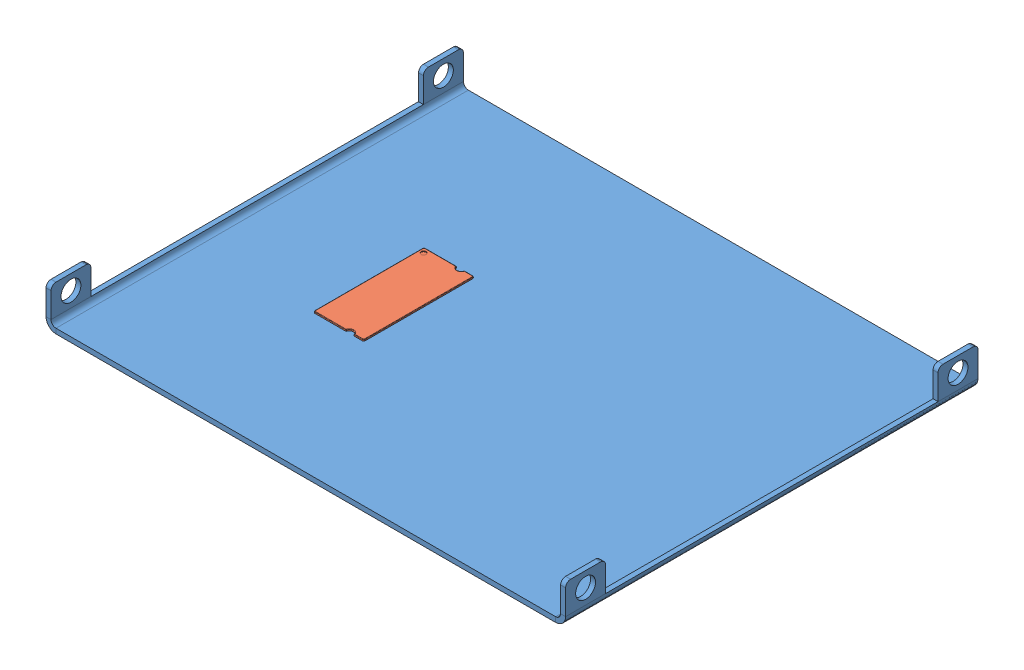
SolidWorks assembly Spirit2U - OBC Shelf, configuration Default. Lengths in mm.
Overall size (104.07 13.8 82.6).
2 component instances, 2 part files, 4 mates.
Components (placement in the parent):
- Spirit2U Shelf 1-1: Spirit2U Shelf 1 [Default] at origin size (104.07 8 82.6)
- OBC-1: OBC [Default] at (12.207 -2.7956 -56.865) x (1 0 0) z (0 -1 0) size (65.14 40 7.07)
Mates (geometry in assembly coordinates):
- Coincident125: coincident: plane of Spirit2U Shelf 1-1 through (0 -1 0) normal (0 -1 0); plane of OBC-1 through (7.207 -1 -23.135) normal (0 1 0)
- Distance15: distance = 30 mm: plane of OBC-1 through (74.072 -1 -42.54) normal (1 0 0); plane of Spirit2U Shelf 1-1 through (104.072 0 0) normal (1 0 0)
- Distance23: distance = 20 mm: plane of OBC-1 through (70.937 -1 -20) normal (0 0 1); plane of Spirit2U Shelf 1-1 through (0 -1 0) normal (0 0 1)
- Coincident126: coordinate: point of Spirit2U Shelf 1-1; point of assembly
